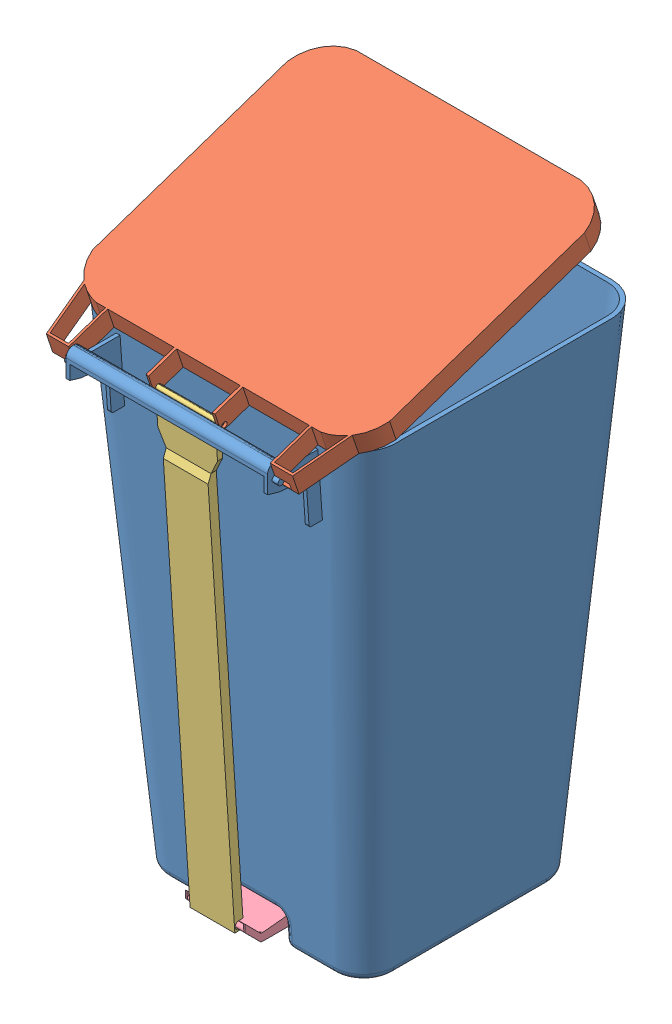
SolidWorks assembly Smart Bin Assembly, configuration Default. Lengths in mm.
Overall size (398 796.55 446.35).
4 component instances, 4 part files, 6 mates.
Components (placement in the parent):
- Bin Bottom-1: Bin Bottom [Default] at (121.9411 -34.8329 571.2183) size (390.06 660.08 446.35)
- Bin Top-1: Bin Top [Default] at (121.9411 685.9136 563.0741) x (1 0 0) z (0 0.947336 0.320241) size (398 423.12 27)
- Paddle middle-1: Paddle middle [Default] at (89.1435 316.3383 778.8171) x (0 0.997795 0.06637) z (1 0 0) size (620 11.62 90)
- pedal-1: pedal [Default] at (121.9411 -8.7954 591.2332) x (1 0 0) z (0 -0.999998 0.001871) size (105 361.53 31.53)
Mates (geometry in assembly coordinates):
- Coincident5: coincident anti-aligned: plane of Bin Bottom-1 through (256.9411 528.1671 769.0209) normal (1 0 0); plane of Bin Top-1 through (256.9411 536.8968 728.0406) normal (-1 0 0)
- Concentric1: concentric aligned: cylinder of Bin Bottom-1 through (264.9411 604.9573 817.5171) axis (-1 0 0) radius 4; cylinder of Bin Top-1 through (276.9411 604.9573 817.5171) axis (-1 0 0) radius 4
- Concentric2: concentric anti-aligned: cylinder of Bin Bottom-1 through (186.9411 -0.8329 571.2183) axis (-1 0 0) radius 5; cylinder of pedal-1 through (71.9411 -0.8329 571.2183) axis (1 0 0) radius 1.7763
- Distance1: distance = 5 mm anti-aligned: plane of Bin Bottom-1 through (166.9411 -4.8329 381.1622) normal (-1 0 0); plane of pedal-1 through (161.9411 -8.7954 591.2332) normal (1 0 0)
- Concentric3: concentric anti-aligned: cylinder of Bin Top-1 through (60.0715 612.3256 796.3754) axis (1 0 0) radius 3.5; cylinder of Paddle middle-1 through (164.1435 612.3256 796.3754) axis (-1 0 0) radius 3.5
- Concentric4: concentric aligned: cylinder of Paddle middle-1 through (149.1435 3.5162 758.2104) axis (-1 0 0) radius 5; cylinder of pedal-1 through (161.9411 3.5162 758.2104) axis (-1 0 0) radius 3.5
